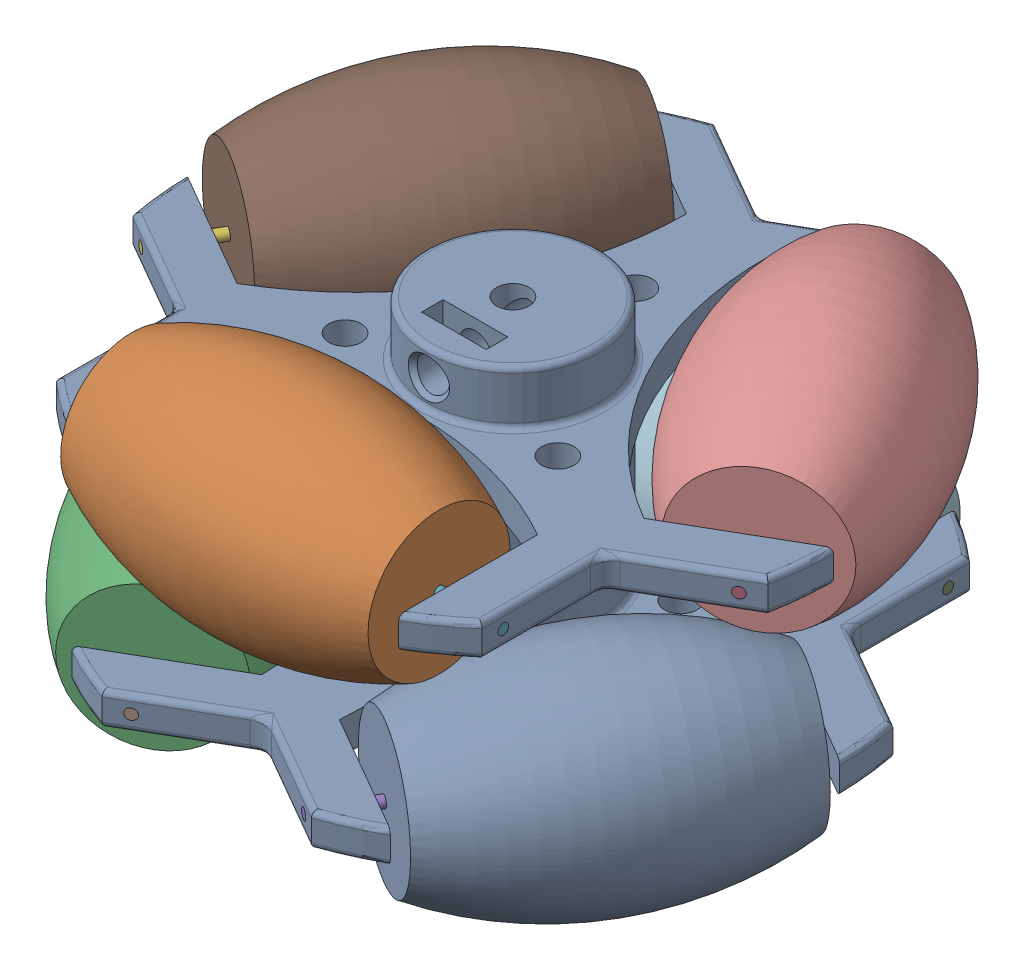
SolidWorks assembly omniwheelSWASM, configuration Default. Lengths in mm.
Overall size (68.54 38.31 62.24).
13 component instances, 3 part files, 10 mates.
Components (placement in the parent):
- omniwheelFrameSW-1: omniwheelFrameSW [Default] at (-278.1985 1.8688 70.1246) size (60.06 25.35 56.8)
- omniwheelWheelSW-4: omniwheelWheelSW [Default] at (-14.0904 20.7111 63.7169) x (0 0.084521 0.996422) z (0 0.996422 -0.084521) size (19.86 28.48 19.86)
- omniwheelWheelSW-6: omniwheelWheelSW [Default] at (-23.9332 3.3511 40.3301) x (0.865486 -0.035303 -0.499688) z (-0.030574 -0.999377 0.017652) size (19.86 28.48 19.86)
- omniwheelRodSW-1: omniwheelRodSW [Default] at (8.6013 20.6688 15.2172) x (-0.84615 -0.213012 0.488525) z (0.5 0 0.866025) size (1 1 39.44)
- omniwheelRodSW-5: omniwheelRodSW [Default] at (28.3208 3.3688 35.8331) x (0.850704 -0.187269 0.491154) z (-0.5 0 0.866025) size (1 1 39.44)
- omniwheelRodSW-3: omniwheelRodSW [Default] at (-27.1066 20.6688 49.3723) x (0.84615 -0.213012 0.488525) z (0.5 0 -0.866025) size (1 1 39.44)
- omniwheelRodSW-4: omniwheelRodSW [Default] at (20.3266 20.6688 63.2186) x (0 -0.213012 -0.97705) z (-1 0 0) size (1 1 39.44)
- omniwheelRodSW-6: omniwheelRodSW [Default] at (-7.3871 3.3688 69.9883) x (-0.850704 -0.187269 0.491154) z (-0.5 0 -0.866025) size (1 1 39.44)
- omniwheelRodSW-7: omniwheelRodSW [Default] at (-19.1124 3.3688 21.9868) x (0 -0.187269 -0.982309) z (1 0 0) size (1 1 39.44)
- omniwheelWheelSW-7: omniwheelWheelSW [Default] at (26.2412 20.7111 44.774) x (0.862926 0.084521 -0.498211) z (-0.073198 0.996422 0.042261) size (19.86 28.48 19.86)
- omniwheelWheelSW-8: omniwheelWheelSW [Default] at (-10.3295 20.7111 19.3172) x (-0.862926 0.084521 -0.498211) z (0.073198 0.996422 0.042261) size (19.86 28.48 19.86)
- omniwheelWheelSW-9: omniwheelWheelSW [Default] at (14.8454 3.3511 22.4865) x (0 -0.035303 0.999377) z (0 -0.999377 -0.035303) size (19.86 28.48 19.86)
- omniwheelWheelSW-10: omniwheelWheelSW [Default] at (10.9091 3.3511 64.9915) x (-0.865486 -0.035303 -0.499688) z (0.030574 -0.999377 0.017652) size (19.86 28.48 19.86)
Mates (geometry in assembly coordinates):
- Concentric5: concentric anti-aligned: circle of omniwheelFrameSW-1; circle of omniwheelRodSW-1
- Concentric6: concentric aligned: circle of omniwheelFrameSW-1; circle of omniwheelRodSW-1
- Coincident11: coincident aligned: circle of omniwheelFrameSW-1; circle of omniwheelRodSW-1
- Concentric7: concentric anti-aligned: cylinder of omniwheelWheelSW-4 through (-14.0904 20.6688 63.2186) axis (-1 0 0) radius 0.5; cylinder of omniwheelRodSW-4 through (-19.1134 20.6688 63.2186) axis (1 0 0) radius 0.5
- Coincident17: coincident aligned: circle of omniwheelFrameSW-1; circle of omniwheelRodSW-5
- Concentric8: concentric anti-aligned: cylinder of omniwheelWheelSW-6 through (-24.366 3.3688 40.58) axis (-0.5 0 -0.866025) radius 0.5; cylinder of omniwheelRodSW-6 through (-27.1071 3.3688 35.8322) axis (0.5 0 0.866025) radius 0.5
- LimitDistance1: limit distance = 0.5412 mm anti-aligned: plane of omniwheelWheelSW-4 through (-14.0904 20.7111 63.7169) normal (-1 0 0); plane of omniwheelFrameSW-1 through (-14.6316 22.1688 70.1246) normal (1 0 0)
- LimitDistance2: limit distance = 1.4592 mm anti-aligned: plane of omniwheelWheelSW-4 through (14.3866 20.7111 63.7169) normal (1 0 0); plane of omniwheelFrameSW-1 through (15.8458 22.1688 70.1246) normal (-1 0 0)
- LimitDistance3: limit distance = 1.0004 mm anti-aligned: plane of omniwheelWheelSW-6 through (-23.9332 3.3511 40.3301) normal (-0.5 0 -0.866025); plane of omniwheelFrameSW-1 through (-228.0338 4.8688 157.0125) normal (0.5 0 0.866025)
- LimitDistance4: limit distance = 1 mm anti-aligned: plane of omniwheelFrameSW-1 through (-212.7951 4.8688 183.4067) normal (-0.5 0 -0.866025); plane of omniwheelWheelSW-6 through (-9.6947 3.3511 64.9919) normal (0.5 0 0.866025)
